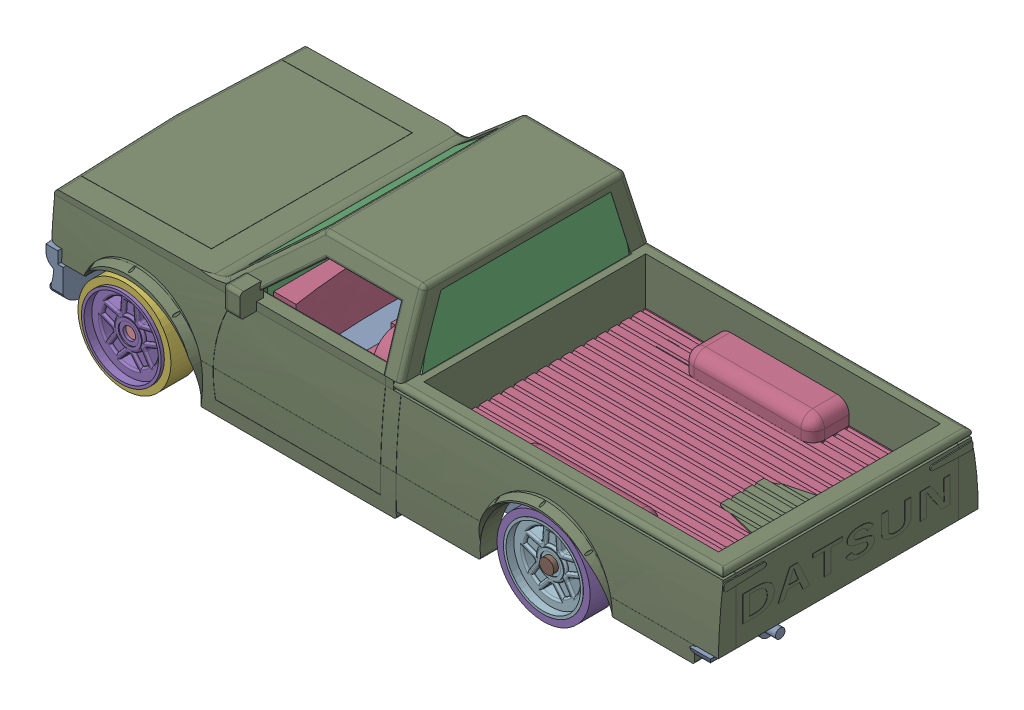
SolidWorks assembly Assem TRUCK 2, configuration Default. Lengths in mm.
Overall size (74.31 21.69 30.88).
14 component instances, 7 part files, 11 mates.
Components (placement in the parent):
- BOTTOM PART-1: BOTTOM PART [Default] at (-9.2459 21.8905 -4.6021) x (1 0 0.000683) z (-0.000683 0 1) size (73.68 7.54 28.82)
- glass trruck part-1: glass trruck part [Default] at (25.0886 29.3999 -25.9696) size (21.34 14.62 22.86)
- MIDD-1: MIDD [Default] at (62.4934 23.2139 -35.4373) x (1 0 0) z (0 -0.00455 0.99999) size (72.14 8.89 24.01)
- star wheel-1: star wheel [Default] at (2.7257 23.4179 10.8824) x (1 0 0.000683) z (-0.000683 0 1) size (9.25 9.25 2.72)
- tire-1: tire [Default] at (2.7263 23.4179 9.8887) x (1 0 0.000683) z (-0.000683 0 1) size (10.03 10.03 3.05)
- TOP TRUCK PART-1: TOP TRUCK PART [Default] at (31.9496 32.2196 8.0302) x (0 0 1) z (-1 0 0) size (30.88 20.22 72.79)
- axle truck-2: axle truck [Default] at (2.7276 23.4179 8.0589) x (0.000683 0 -1) z (1 0 0.000683) size (26.42 1.52 1.52)
- axle truck-3: axle truck [Default] at (47.1301 23.5573 7.7401) x (0 0 -1) z (1 0 0) size (26.42 1.52 1.52)
- star wheel-2: star wheel [Default] at (47.1301 23.5573 9.7655) size (9.25 9.25 2.72)
- star wheel-3: star wheel [Default] at (47.1301 23.5573 -21.3961) x (-1 0 0) z (0 0 -1) size (9.25 9.25 2.72)
- star wheel-4: star wheel [Default] at (2.7478 23.4179 -21.475) x (-1 0 -0.000683) z (0.000683 0 -1) size (9.25 9.25 2.72)
- tire-2: tire [Default] at (2.7441 23.4179 -16.0904) x (1 0 0.000683) z (-0.000683 0 1) size (10.03 10.03 3.05)
- tire-3: tire [Default] at (47.1301 23.5573 -15.9304) size (10.03 10.03 3.05)
- tire-4: tire [Default] at (47.1301 23.5573 9.0842) size (10.03 10.03 3.05)
Mates (geometry in assembly coordinates):
- Coincident1: coincident anti-aligned: plane of glass trruck part-1 through (11.2994 38.9386 -6.1491) normal (0 1 0); plane of TOP TRUCK PART-1 through (11.6296 38.9386 8.0302) normal (0 -1 0)
- Coincident2: coincident anti-aligned: plane of MIDD-1 through (54.2028 31.5958 -35.3992) normal (1 0 0); plane of TOP TRUCK PART-1 through (54.2028 9.3596 8.0302) normal (-1 0 0)
- Coincident3: coincident anti-aligned: plane of MIDD-1 through (62.4934 30.2497 -35.4053) normal (0 0.99999 0.00455); plane of TOP TRUCK PART-1 through (36.0442 30.0521 8.0204) normal (0 -0.99999 -0.00455)
- Concentric3: concentric aligned: cylinder of star wheel-1 through (2.7287 23.4179 6.4955) axis (-0.000683 0 1) radius 4.6228; cylinder of tire-1 through (2.7289 23.4179 6.0787) axis (-0.000683 0 1) radius 4.826
- Concentric6: concentric aligned: circle of star wheel-1; cylinder of axle truck-2 through (2.7453 23.4179 -17.849) axis (-0.000683 0 1) radius 0.635
- Concentric7: concentric anti-aligned: cylinder of axle truck-3 through (47.1301 23.5573 -18.1679) axis (0 0 1) radius 0.635; circle of star wheel-3
- Concentric8: concentric anti-aligned: cylinder of axle truck-2 through (2.7453 23.4179 -17.849) axis (-0.000683 0 1) radius 0.635; circle of star wheel-4
- Concentric9: concentric aligned: cylinder of axle truck-3 through (47.1301 23.5573 -18.1679) axis (0 0 1) radius 0.635; circle of star wheel-2
- Concentric10: concentric anti-aligned: cylinder of star wheel-4 through (2.7448 23.4179 -17.0882) axis (0.000683 0 -1) radius 4.6228; cylinder of tire-2 through (2.7467 23.4179 -19.9004) axis (-0.000683 0 1) radius 4.826
- Concentric11: concentric anti-aligned: cylinder of star wheel-3 through (47.1301 23.5573 -17.0092) axis (0 0 -1) radius 4.6228; cylinder of tire-3 through (47.1301 23.5573 -19.7404) axis (0 0 1) radius 4.826
- Concentric12: concentric aligned: cylinder of star wheel-2 through (47.1301 23.5573 5.3786) axis (0 0 1) radius 4.6228; cylinder of tire-4 through (47.1301 23.5573 5.2742) axis (0 0 1) radius 4.826
